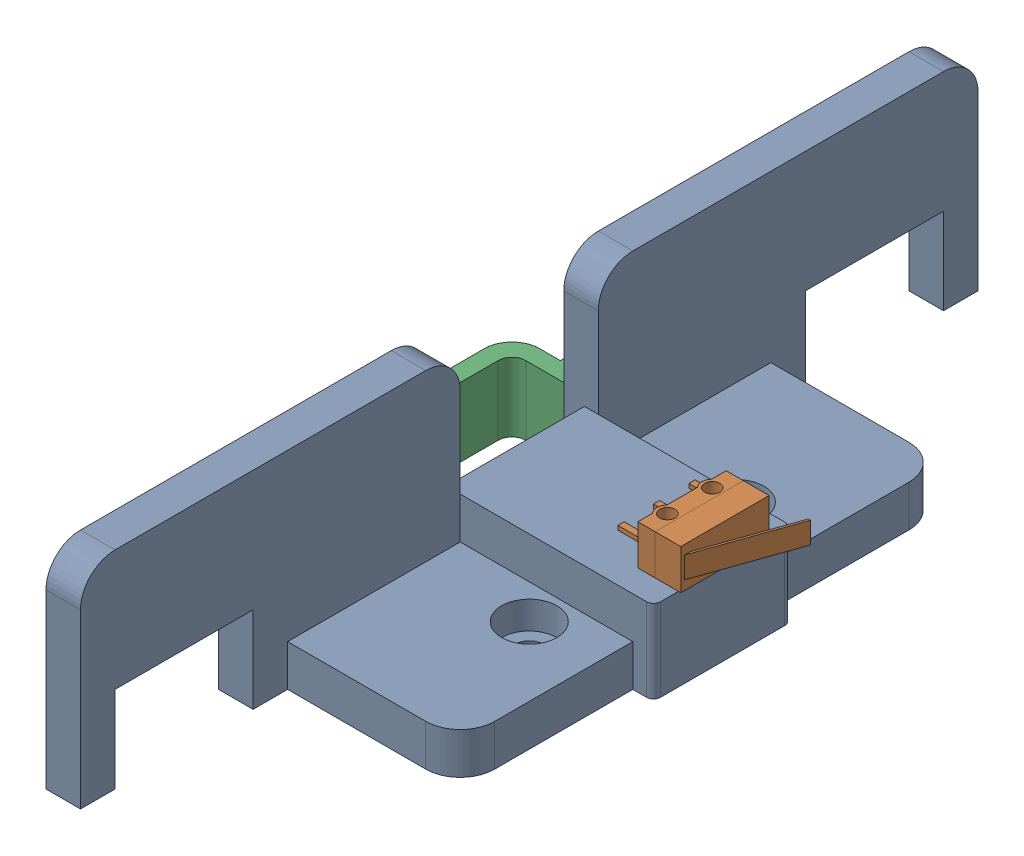
SolidWorks assembly EndStop_YLeft, configuration Default. Lengths in mm.
Overall size (50.59 30 130).
3 component instances, 3 part files, 9 mates.
Components (placement in the parent):
- WW0012-1: WW0012 [Default] at origin size (33 30 130)
- Limit Switch-1: Limit Switch [Default] at (3.35 12 6.4) x (0 0 1) z (-1 0 0) size (14.05 5.8 14.66)
- WW0037_3-1: WW0037_3 [Default] at (-40 6 0) x (0 0 -1) z (0 1 0) size (50 12.5 10)
Mates (geometry in assembly coordinates):
- Width1: width anti-aligned: plane of WW0012-1 through (-30 12 -10) normal (0 0 1); plane of Limit Switch-1 through (-30 12 10) normal (0 0 -1); plane of WW0012-1 through (-2.87 12 -6.4) normal (0 0 -1); plane of Limit Switch-1 through (-2.87 12 6.4) normal (0 0 1)
- Coincident1: coincident anti-aligned: plane of WW0012-1 through (0 12 0) normal (0 1 0); plane of Limit Switch-1 through (-2.87 12 6.4) normal (0 -1 0)
- Concentric1: concentric anti-aligned: cylinder of WW0012-1 through (-1.75 7.5 -3.25) axis (0 1 0) radius 1.6; cylinder of Limit Switch-1 through (-1.75 12 -3.25) axis (0 -1 0) radius 1.1
- Coincident2: coincident anti-aligned: plane of WW0012-1 through (-30 6 -65) normal (-1 0 0); plane of WW0037_2-1 through (-30 1 -15) normal (1 0 0)
- Parallel1: parallel aligned: plane of WW0012-1 through (0 0 0) normal (0 -1 0); plane of WW0037_2-1 through (-36 1 0) normal (0 -1 0)
- Concentric2: concentric aligned: cylinder of WW0012-1 through (-25.9 6 -20) axis (-1 0 0) radius 2.5; cylinder of WW0037_2-1 through (-30.95 6 -20) axis (-1 0 0) radius 3.05
- Coincident3: coincident anti-aligned: plane of WW0012-1 through (-30 6 -65) normal (-1 0 0); plane of WW0037_3-1 through (-30 11 -15) normal (1 0 0)
- Concentric3: concentric aligned: cylinder of WW0012-1 through (-25.9 6 -20) axis (-1 0 0) radius 2.5; cylinder of WW0037_3-1 through (-35.5 6 -20) axis (-1 0 0) radius 1.7
- Parallel2: parallel aligned: plane of WW0012-1 through (0 0 0) normal (0 -1 0); plane of WW0037_3-1 through (-40 1 0) normal (0 -1 0)
